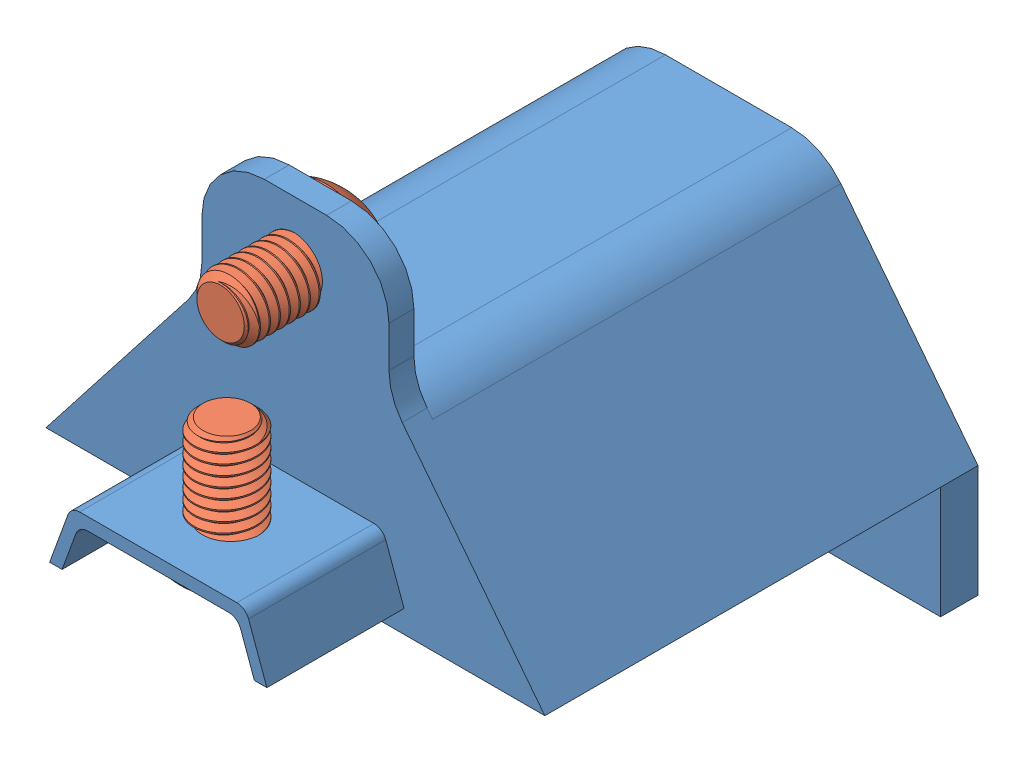
SolidWorks assembly Lower rack holder, configuration Default. Lengths in mm.
Overall size (40 35 45.73).
3 component instances, 2 part files, 4 mates.
Components (placement in the parent):
- rack bracket-1: rack bracket [Default] at origin size (40 35 45.73)
- 92095A211_Button Head Hex Drive Screw (2) - Copy-1: 92095A211_Button Head Hex Drive Screw (2) - Copy [10mm length] at (20 11.75 40.23) x (1 0 0) z (0 -1 0) size (9.5 9.5 11.19)
- 92095A211_Button Head Hex Drive Screw (2) - Copy-2: 92095A211_Button Head Hex Drive Screw (2) - Copy [10mm length] at (20 30 29.98) x (1 0 0) z (0 0 -1) size (9.5 9.5 11.19)
Mates (geometry in assembly coordinates):
- Coincident12: coincident anti-aligned: plane of rack bracket-1 through (27.5 35 32.73) normal (0 0 -1); plane of 92095A211_Button Head Hex Drive Screw (2) - Copy-2 through (24.75 30 32.73) normal (0 0 1)
- Concentric5: concentric anti-aligned: circle of rack bracket-1; circle of 92095A211_Button Head Hex Drive Screw (2) - Copy-2
- Coincident14: coincident anti-aligned: plane of rack bracket-1 through (13.636 14.5 45.73) normal (0 -1 0); plane of 92095A211_Button Head Hex Drive Screw (2) - Copy-1 through (24.75 14.5 40.23) normal (0 1 0)
- Concentric6: concentric aligned: circle of rack bracket-1; circle of 92095A211_Button Head Hex Drive Screw (2) - Copy-1
